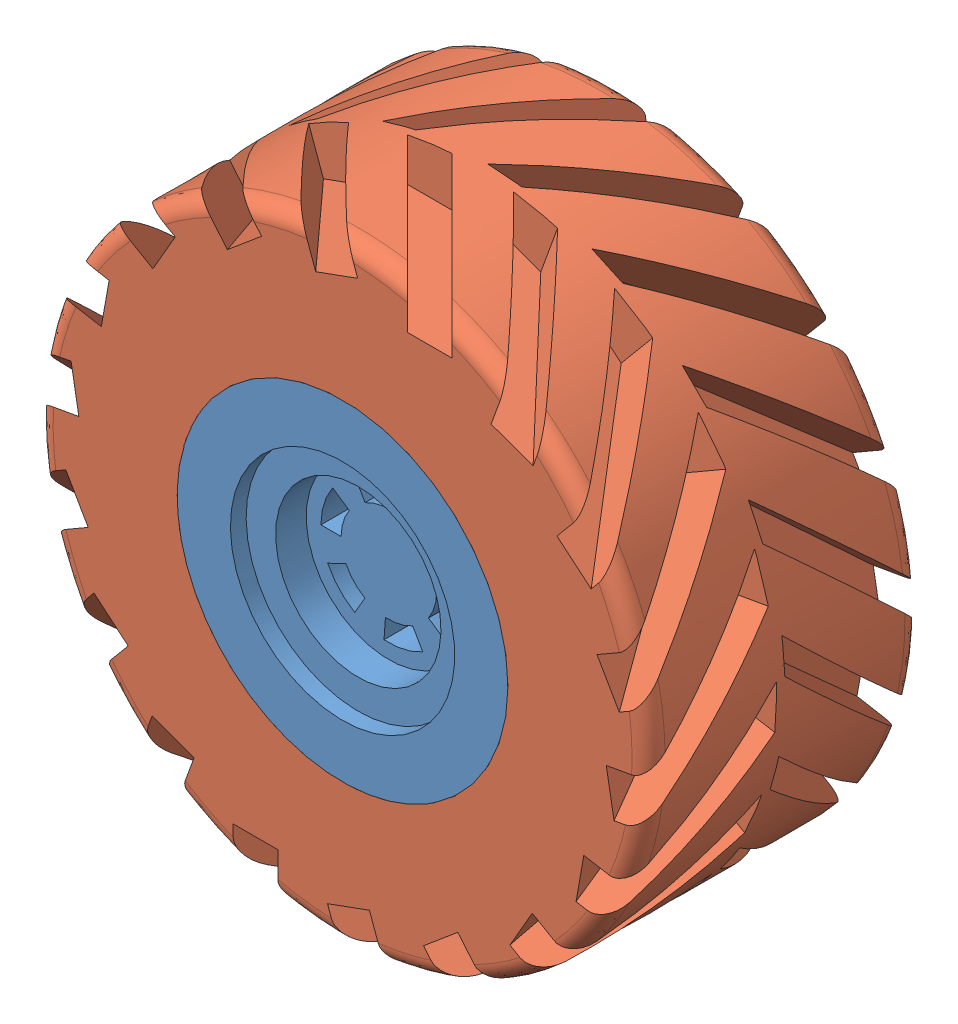
SolidWorks assembly Rear Wheel Assembly, configuration Default. Lengths in mm.
Overall size (94.56 94.48 42.49).
2 component instances, 2 part files, 2 mates.
Components (placement in the parent):
- Rear Wheel Hub-1: Rear Wheel Hub [Default] at (39.9984 62.3303 90.5124) x (0.280155 -0.959955 0) z (0 0 1) size (50.8 50.8 41.91)
- Rear Tire-2: Rear Tire [Default] at (39.9984 62.3303 69.5574) size (94.56 94.48 42.49)
Mates (geometry in assembly coordinates):
- Concentric3: concentric aligned: circle of Rear Wheel Hub-1; circle of Rear Tire-2
- Coincident6: coincident aligned: plane of Rear Wheel Hub-1 through (39.9984 62.3303 69.5574) normal (0 0 -1); plane of Rear Tire-2 through (39.9984 62.3303 69.5574) normal (0 0 -1)
